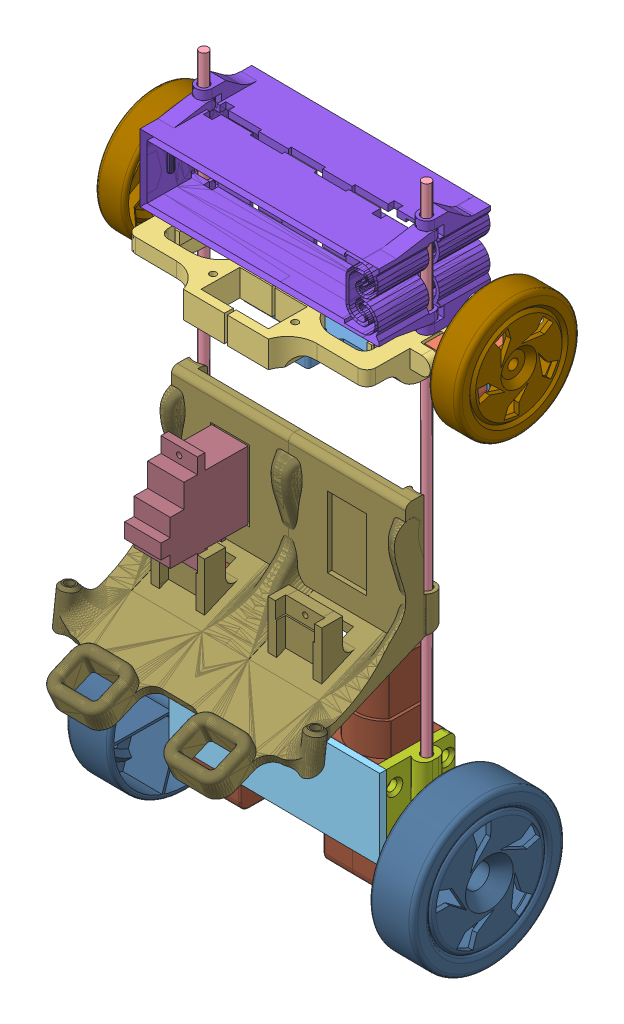
SolidWorks assembly Ensamblaje, configuration Predeterminado. Lengths in mm.
Overall size (124.39 220.6 96.36).
24 component instances, 13 part files, 29 mates.
Components (placement in the parent):
- 15+11+16 (Direccion)-1: 15+11+16 (Direccion) [Predeterminado] at (16.0119 -4.6293 180.9159) x (-0.999962 0 -0.008727) z (0.008727 0 -0.999962) size (114 21 49.38)
  - 15-1: 15 [Predeterminado] at (-56.802 1.6746 98) size (98 6 26)
  - 16R-1: 16R [Predeterminado] at (-53.802 19.6746 97.62) x (-1 0 0) z (0 -1 0) size (15 24 21)
  - 16R-5: 16R [16L] at (30.198 19.6746 97.62) x (-1 0 0) z (0 -1 0) size (15 24 21)
  - 11R-8: 11R [Predeterminado] at (-46.802 11.6746 87.24) x (0 1 0) z (-1 0 0) size (11.54 34.26 47.5)
  - 11R-12: 11R [11L] at (-45.802 11.6746 87.24) x (0 1 0) z (-1 0 0) size (11.54 34.26 47.5)
- Palillo 180x3mm-1: Palillo 180x3mm [Predeterminado] at (66.5733 58.5251 94.1139) x (1 0 0) z (0 -1 0) size (3 3 180)
- Palillo 180x3mm-2: Palillo 180x3mm [Predeterminado] at (-9.4238 58.5251 93.4507) x (-0.109084 0 -0.994033) z (0 -1 0) size (3 3 180)
- Llantas Traseras-1: Llantas Traseras [Predeterminado] at (25.9021 -143.9749 93.7837) x (-0.999962 0 -0.008727) z (0 1 0) size (82 25.5 27.12)
  - 0-1: 0 [Predeterminado] at (-2.6726 -0.0247 28) size (72 25.5 27.12)
  - 1L-1: 1L [Predeterminado] at (35.3274 -0.0247 37.5) x (0 0 -1) z (1 0 0) size (27.12 23 8)
  - 1R-1: 1R [Predeterminado] at (-40.6726 -0.0247 37.5) x (0 0 -1) z (1 0 0) size (27.12 23 8)
- Portapilas-1: Portapilas [Predeterminado] at (-4722.5243 -565.076 82894.9083) x (-0.999962 0 -0.008727) z (0.008727 0 -0.999962) size (81.5 33.48 37.48)
  - Portapila 18650-1: Portapila 18650 [Portapila B] at (-32851.1916 596.8515 73014.9) size (81.5 33.48 21.49)
  - Portapila 18650-2: Portapila 18650 [Predeterminado] at (-32934.0303 596.8612 92551.9559) x (1 0 0) z (0 0 -1) size (81.5 26.68 21.49)
- LlantaF-1: LlantaF [Predeterminado] at (80.6372 12.0453 86.8563) x (0.008727 0 -0.999962) z (0.999962 0 0.008727) size (41 41 10)
- LlantaT-1: LlantaT [Predeterminado] at (72.9731 -136.5749 94.1697) x (0 -1 0) z (0.999962 0 0.008727) size (51 51 23)
- LlantaF-2: LlantaF [Predeterminado] at (-23.3589 12.0453 85.9488) x (0.008504 0.224218 -0.974502) z (-0.999962 0 -0.008727) size (41 41 10)
- LlantaT-2: LlantaT [Predeterminado] at (-15.8236 -136.5749 93.3948) x (0 -1 0) z (-0.999962 0 -0.008727) size (51 51 23)
- motor-1: motor [Default] at (-4.424 -136.5749 93.4943) x (-0.008727 0 0.999962) z (0.999962 0 0.008727) size (22.6 65.53 37.6)
- motor-2: motor [Default] at (42.7742 -136.5749 93.9062) x (-0.008727 0 0.999962) z (0.999962 0 0.008727) size (22.6 65.53 37.6)
- Asientos + Servos-1: Asientos + Servos [Predeterminado] at (24.8032 -154.7491 108.3021) x (-0.999962 0.000001 -0.008726) z (0.000001 1 0) size (90 66.51 67.67)
  - 2-1: 2 [Predeterminado] at (-12.6807 -14.5522 82.7944) size (90 66.51 67.67)
  - Servo 9G-2: Servo 9G [Predeterminado] at (10.1374 4.6978 102.2944) x (0 0 -1) z (1 0 0) size (33.4 29.2 12.4)
Mates (geometry in assembly coordinates):
- Concéntrica1: concentric: circle of assembly; circle of assembly; circle of 15+11+16 (Direccion)-1/11R-12; circle of Palillo 180x3mm-2
- Concéntrica2: concentric: circle of assembly; circle of assembly; circle of 15+11+16 (Direccion)-1/11R-8; circle of Palillo 180x3mm-1
- Coincidente1: coincident: plane of assembly; plane of assembly; plane of Palillo 180x3mm-1 through (66.5733 58.5251 94.1139) normal (0 1 0); plane of Palillo 180x3mm-2 through (-9.4238 58.5251 93.4507) normal (0 1 0)
- Concéntrica3: concentric: circle of assembly; circle of assembly; circle of Palillo 180x3mm-2; circle of Llantas Traseras-1/1L-1
- Concéntrica4: concentric: circle of assembly; circle of assembly; circle of Palillo 180x3mm-1; circle of Llantas Traseras-1/1R-1
- Coincidente3: coincident: plane of assembly; plane of assembly; plane of Palillo 180x3mm-1 through (66.5733 -121.4749 94.1139) normal (0 -1 0); plane of Llantas Traseras-1/1R-1 through (66.5733 -121.4749 94.1139) normal (0 1 0)
- Concéntrica5: concentric: circle of assembly; circle of assembly; circle of Palillo 180x3mm-2; circle of Portapilas-1/Portapila 18650-1
- Concéntrica6: concentric: circle of assembly; circle of assembly; circle of Palillo 180x3mm-1; circle of Portapilas-1/Portapila 18650-1
- Distancia1: distance = 10 mm: plane of assembly; plane of assembly; plane of Palillo 180x3mm-2 through (-9.4238 58.5251 93.4507) normal (0 1 0); plane of Portapilas-1/Portapila 18650-1 through (57.7068 48.5251 94.5266) normal (0 1 0)
- Distancia límite1: limit distance = 0 mm: plane of assembly; plane of assembly; plane of Portapilas-1/Portapila 18650-1 through (57.7068 15.0453 94.5266) normal (0 -1 0); plane of 15+11+16 (Direccion)-1/11R-12 through (-12.4962 15.0453 101.7382) normal (0 1 0)
- Concéntrica7: concentric: circle of assembly; circle of assembly; circle of 15+11+16 (Direccion)-1/16R-1; circle of LlantaF-1
- Concéntrica8: concentric: circle of assembly; circle of assembly; circle of 15+11+16 (Direccion)-1/16R-5; circle of LlantaF-2
- Coincidente5: coincident: plane of assembly; plane of assembly; plane of 15+11+16 (Direccion)-1/16R-1 through (85.6632 9.0453 83.9001) normal (0.999962 0 0.008727); plane of LlantaF-1 through (85.637 12.0453 86.9) normal (-0.999962 0 -0.008727)
- Coincidente6: coincident: plane of assembly; plane of assembly; plane of 15+11+16 (Direccion)-1/16R-5 through (-28.3325 9.0453 82.9052) normal (-0.999962 0 -0.008727); plane of LlantaF-2 through (-28.3587 12.0453 85.9051) normal (0.999962 0 0.008727)
- Concéntrica10: concentric: circle of assembly; circle of assembly; circle of Llantas Traseras-1/1L-1; circle of motor-1
- Concéntrica11: concentric: circle of assembly; circle of assembly; circle of Llantas Traseras-1/1L-1; circle of motor-1
- Concéntrica12: concentric: circle of assembly; circle of assembly; circle of Llantas Traseras-1/1R-1; circle of motor-2
- Concéntrica13: concentric: circle of assembly; circle of assembly; circle of Llantas Traseras-1/1R-1; circle of motor-2
- Coincidente7: coincident: plane of assembly; plane of assembly; plane of Llantas Traseras-1/1R-1 through (61.5735 -125.4749 94.0702) normal (-0.999962 0 -0.008727); plane of motor-2 through (61.5735 -136.5749 94.0702) normal (0.999962 0 0.008727)
- Coincidente8: coincident: plane of assembly; plane of assembly; plane of Llantas Traseras-1/1L-1 through (-4.424 -125.4749 93.4943) normal (0.999962 0 0.008727); plane of motor-1 through (-4.424 -136.5749 93.4943) normal (-0.999962 0 -0.008727)
- Concéntrica14: concentric: circle of assembly; circle of assembly; circle of LlantaT-2; circle of motor-1
- Paralelo2: parallel: line of assembly; line of assembly; line of LlantaT-2 through (-7.8435 -134.5905 95.7145) axis (0 -1 0); line of motor-1 through (-13.8393 -134.5624 95.2122) axis (0 -1 0)
- Coincidente11: coincident: plane of assembly; plane of assembly; plane of LlantaT-2 through (-13.8236 -136.5749 93.4123) normal (0.999962 0 0.008727); plane of motor-1 through (-13.8236 -136.5749 93.4123) normal (-0.999962 0 -0.008727)
- Paralelo3: parallel: line of assembly; line of assembly; line of LlantaT-1 through (64.9537 -138.5592 96.3498) axis (0 1 0); line of motor-2 through (70.9574 -134.5624 95.9522) axis (0 -1 0)
- Concéntrica16: concentric: circle of assembly; circle of assembly; circle of LlantaT-1; circle of motor-2
- Coincidente13: coincident: plane of assembly; plane of assembly; plane of LlantaT-1 through (70.9731 -136.5749 94.1523) normal (-0.999962 0 -0.008727); plane of motor-2 through (70.9731 -136.5749 94.1523) normal (0.999962 0 0.008727)
- Concéntrica21: concentric: circle of assembly; circle of assembly; circle of Palillo 180x3mm-1; circle of Asientos + Servos-1/2-1
- Paralelo4: parallel: plane of assembly; plane of assembly; plane of 15+11+16 (Direccion)-1/11R-12 through (-6.6857 -9.6071 123.4757) normal (-0.008727 0 0.999962); plane of Asientos + Servos-1/Servo 9G-2 through (2.1276 -52.4546 124.0526) normal (-0.008727 0 0.999962)
- Distancia4: distance = 25 mm: plane of assembly; point of assembly; plane of 15+11+16 (Direccion)-1/15-1 through (73.7018 -5.9547 79.4155) normal (0 -1 0); point of Asientos + Servos-1/2-1
